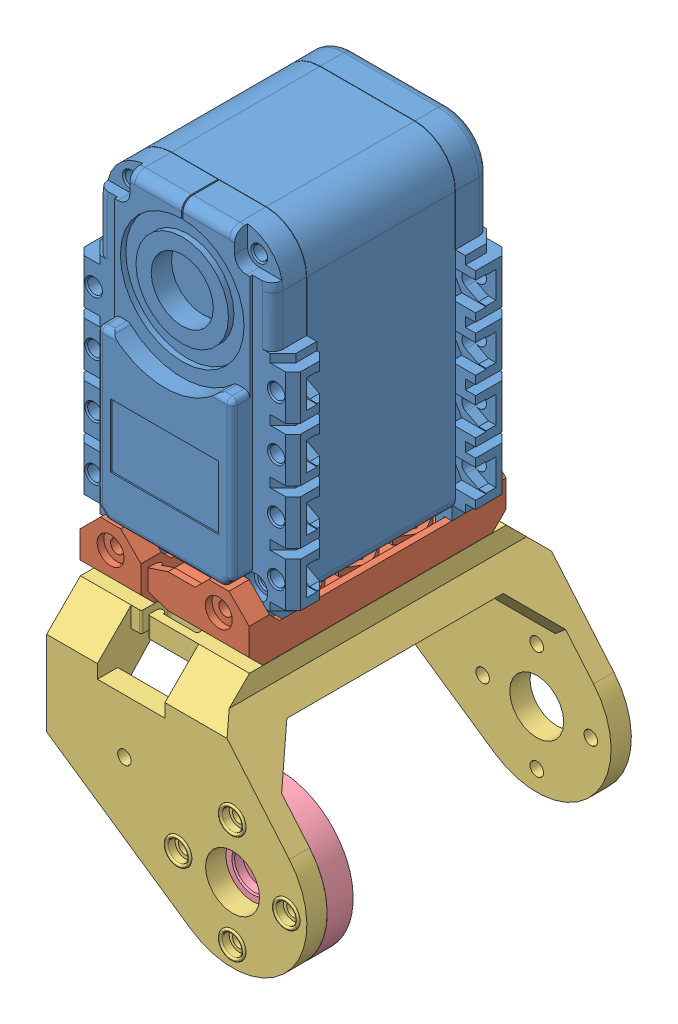
SolidWorks assembly Femur_right, configuration Default. Lengths in mm.
Overall size (42.04 87.04 48.5).
4 component instances, 4 part files, 10 mates.
Components (placement in the parent):
- ServoBody-1: ServoBody [Default] at origin size (32 50.04 38.67)
- F3-1: F3 [Default] at (0.5 -41.5 -13.4) size (25 9 38)
- F1-1: F1 [Default] at (15.5426 -64.5 -13.4003) x (-1 0 0) z (0 0 1) size (38.5 34 48.5)
- ServoHorn-1: ServoHorn [Default] at (15.5426 -64.5 -13.2703) size (22 22 6.71)
Mates (geometry in assembly coordinates):
- Concentric6: concentric anti-aligned: cylinder of ServoHorn-1 through (15.5426 -56.5 5.7597) axis (0 0 1) radius 1.05; cylinder of F1-1 through (15.5426 -56.5 10.5997) axis (0 0 -1) radius 1
- Concentric7: concentric anti-aligned: cylinder of ServoHorn-1 through (15.5426 -72.5 5.7597) axis (0 0 1) radius 1.05; cylinder of F1-1 through (15.5426 -72.5 10.5997) axis (0 0 -1) radius 1
- Coincident12: coincident anti-aligned: plane of F1-1 through (33.2664 -81.3342 7.5997) normal (0 0 -1); plane of ServoHorn-1 through (4.0998 -53.0629 7.5997) normal (0 0 1)
- Coincident23: coincident anti-aligned: plane of F1-1 through (13.042 -41.5 10.5997) normal (0 1 0); plane of F3-1 through (-14 -41.5 -26.15) normal (0 -1 0)
- Coincident27: coincident aligned: plane of F1-1 through (-1.1897 -45.5 -8.4) normal (0 0 -1); plane of F3-1 through (-2.5 -38.5 -8.4) normal (0 0 -1)
- Coincident28: coincident aligned: plane of F1-1 through (3.5 -46 -8.4) normal (-1 0 0); plane of F3-1 through (3.5 -38.5 -18.4) normal (-1 0 0)
- Coincident29: coincident anti-aligned: plane of F3-1 through (-12 -41.5 2.6) normal (0 0 -1); plane of ServoBody-1 through (-14.996 -38.283 2.6) normal (0 0 1)
- Concentric8: concentric anti-aligned: cylinder of F3-1 through (-7.5 -36 2.6) axis (0 0 1) radius 1; cylinder of ServoBody-1 through (-7.5 -36 2.4) axis (0 0 -1) radius 1.1
- Concentric9: concentric aligned: cylinder of F3-1 through (8.5 -36 2.6) axis (0 0 1) radius 1; cylinder of ServoBody-1 through (8.5 -36 0.6) axis (0 0 1) radius 1.1
- Coincident30: coordinate: point of ServoBody-1; point of assembly
